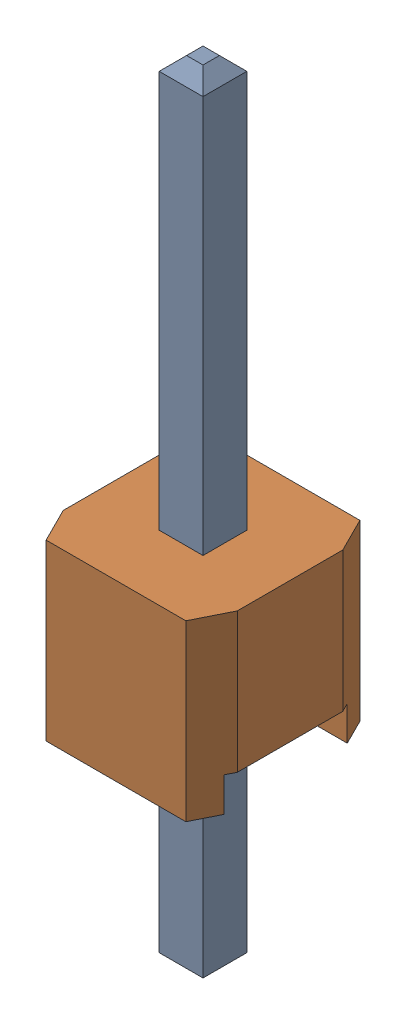
SolidWorks assembly 61300111121, configuration Default. Lengths in mm.
Overall size (2.54 11.54 2.54).
2 component instances, 2 part files, 0 mates.
Components (placement in the parent):
- 6130xx11121_PIN-1: 6130xx11121_PIN [Default] at (0 1.5 0) x (1 0 0) z (0 -1 0) size (0.64 0.64 11.54)
- 61300111121-1: 61300111121 [Default] at origin size (2.54 2.54 2.54)
